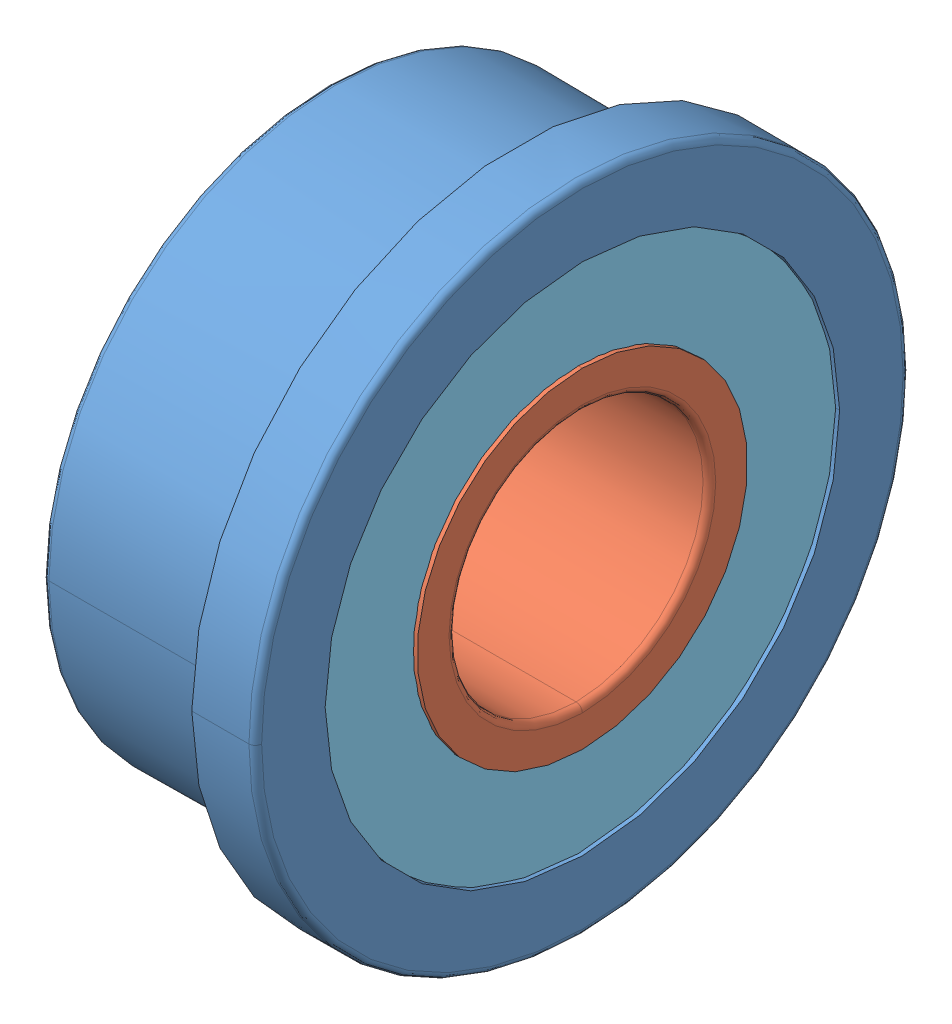
SolidWorks assembly F684ZZ, configuration Default. Lengths in mm.
Overall size (4 10.3 10.3).
14 component instances, 5 part files, 0 mates.
Components (placement in the parent):
- _F684ZZ_Outer_Ring_2-1: _F684ZZ_Outer_Ring_2 [Default] at origin size (4 10.3 10.3)
- _F684ZZ_Inner_Ring_4-1: _F684ZZ_Inner_Ring_4 [Default] x (1 0 0) z (0 -1 0) size (4 5.2 5.2)
- _F684ZZ_Shield1_6-1: _F684ZZ_Shield1_6 [Default] at (0.5 0 0) x (-1 0 0) z (0 -1 0) size (0.19 8.1 8.1)
- _F684ZZ_Ball_8-1: _F684ZZ_Ball_8 [Default] at (2 0 3.25) x (1 0 0) z (0 -1 0) size (1.5 1.5 1.5)
- _F684ZZ_Ball_8-2: _F684ZZ_Ball_8 [Default] at (2 -1.9103 2.6293) x (1 0 0) z (0 -1 0) size (1.5 1.5 1.5)
- _F684ZZ_Ball_8-3: _F684ZZ_Ball_8 [Default] at (2 -3.0909 1.0043) x (1 0 0) z (0 -1 0) size (1.5 1.5 1.5)
- _F684ZZ_Ball_8-4: _F684ZZ_Ball_8 [Default] at (2 -3.0909 -1.0043) x (1 0 0) z (0 -1 0) size (1.5 1.5 1.5)
- _F684ZZ_Ball_8-5: _F684ZZ_Ball_8 [Default] at (2 -1.9103 -2.6293) x (1 0 0) z (0 -1 0) size (1.5 1.5 1.5)
- _F684ZZ_Ball_8-6: _F684ZZ_Ball_8 [Default] at (2 0 -3.25) x (1 0 0) z (0 -1 0) size (1.5 1.5 1.5)
- _F684ZZ_Ball_8-7: _F684ZZ_Ball_8 [Default] at (2 1.9103 -2.6293) x (1 0 0) z (0 -1 0) size (1.5 1.5 1.5)
- _F684ZZ_Ball_8-8: _F684ZZ_Ball_8 [Default] at (2 3.0909 -1.0043) x (1 0 0) z (0 -1 0) size (1.5 1.5 1.5)
- _F684ZZ_Ball_8-9: _F684ZZ_Ball_8 [Default] at (2 3.0909 1.0043) x (1 0 0) z (0 -1 0) size (1.5 1.5 1.5)
- _F684ZZ_Ball_8-10: _F684ZZ_Ball_8 [Default] at (2 1.9103 2.6293) x (1 0 0) z (0 -1 0) size (1.5 1.5 1.5)
- _F684ZZ_Shield2_19-1: _F684ZZ_Shield2_19 [Default] at origin size (0.19 8.1 8.1)
